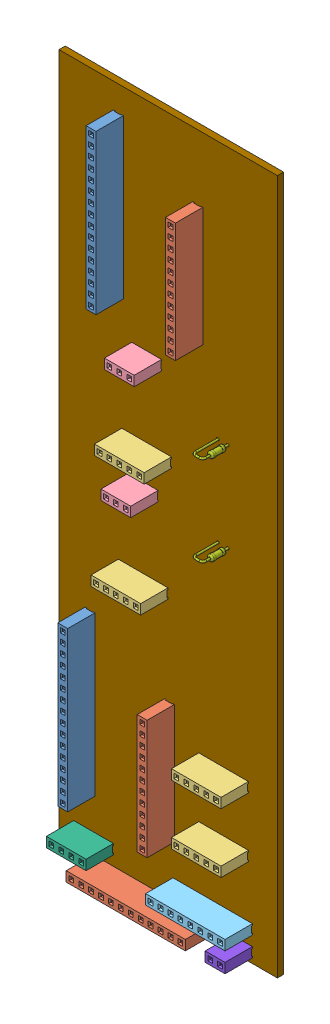
SolidWorks assembly PCB-Step, configuration Default. Lengths in mm.
Overall size (55.88 177.8 10.1).
33 component instances, 9 part files, 0 mates.
Components (placement in the parent):
- PinSocket_1x16_P2.54mm_Vertical.step-1: PinSocket_1x16_P2.54mm_Vertical.step [Default] at (83.82 -25.4 1.65) size (2.54 40.64 10.1)
  - SOLID.step-1: SOLID.step [Default] at origin size (2.54 40.64 10.1)
- PinSocket_1x12_P2.54mm_Vertical.step-1: PinSocket_1x12_P2.54mm_Vertical.step [Default] at (104.14 -35.56 1.65) size (2.54 30.48 10.1)
  - SOLID-0.step-1: SOLID-0.step [Default] at origin size (2.54 30.48 10.1)
- PinSocket_1x05_P2.54mm_Vertical.step-1: PinSocket_1x05_P2.54mm_Vertical.step [Default] at (105.664 -156.972 1.65) x (0 1 0) z (0 0 1) size (2.54 12.7 10.1)
  - SOLID-1.step-1: SOLID-1.step [Default] at origin size (2.54 12.7 10.1)
- PinSocket_1x05_P2.54mm_Vertical.step-2: PinSocket_1x05_P2.54mm_Vertical.step [Default] at (105.664 -172.212 1.65) x (0 1 0) z (0 0 1) size (2.54 12.7 10.1)
  - SOLID-1.step-1: SOLID-1.step [Default] at origin size (2.54 12.7 10.1)
- PinSocket_1x16_P2.54mm_Vertical.step-2: PinSocket_1x16_P2.54mm_Vertical.step [Default] at (76.581 -139.192 1.65) size (2.54 40.64 10.1)
  - SOLID.step-1: SOLID.step [Default] at origin size (2.54 40.64 10.1)
- PinSocket_1x12_P2.54mm_Vertical.step-2: PinSocket_1x12_P2.54mm_Vertical.step [Default] at (96.901 -149.352 1.65) size (2.54 30.48 10.1)
  - SOLID-0.step-1: SOLID-0.step [Default] at origin size (2.54 30.48 10.1)
- PinSocket_1x12_P2.54mm_Vertical.step-3: PinSocket_1x12_P2.54mm_Vertical.step [Default] at (78.74 -193.04 1.65) x (0 1 0) z (0 0 1) size (2.54 30.48 10.1)
  - SOLID-0.step-1: SOLID-0.step [Default] at origin size (2.54 30.48 10.1)
- PinSocket_1x03_P2.54mm_Vertical.step-1: PinSocket_1x03_P2.54mm_Vertical.step [Default] at (88.519 -74.549 1.65) x (0 1 0) z (0 0 1) size (2.54 7.62 10.1)
  - SOLID-2.step-1: SOLID-2.step [Default] at origin size (2.54 7.62 10.1)
- PinSocket_1x05_P2.54mm_Vertical.step-3: PinSocket_1x05_P2.54mm_Vertical.step [Default] at (85.979 -94.869 1.65) x (0 1 0) z (0 0 1) size (2.54 12.7 10.1)
  - SOLID-1.step-1: SOLID-1.step [Default] at origin size (2.54 12.7 10.1)
- PinSocket_1x08_P2.54mm_Vertical.step-1: PinSocket_1x08_P2.54mm_Vertical.step [Default] at (99.06 -187.96 1.65) x (0 1 0) z (0 0 1) size (2.54 20.32 10.1)
  - SOLID-3.step-1: SOLID-3.step [Default] at origin size (2.54 20.32 10.1)
- PinSocket_1x04_P2.54mm_Vertical.step-1: PinSocket_1x04_P2.54mm_Vertical.step [Default] at (73.66 -187.96 1.65) x (0 1 0) z (0 0 1) size (2.54 10.16 10.1)
  - SOLID-4.step-1: SOLID-4.step [Default] at origin size (2.54 10.16 10.1)
- PinSocket_1x03_P2.54mm_Vertical.step-2: PinSocket_1x03_P2.54mm_Vertical.step [Default] at (87.63 -104.013 1.65) x (0 1 0) z (0 0 1) size (2.54 7.62 10.1)
  - SOLID-2.step-1: SOLID-2.step [Default] at origin size (2.54 7.62 10.1)
- PinSocket_1x05_P2.54mm_Vertical.step-4: PinSocket_1x05_P2.54mm_Vertical.step [Default] at (85.09 -124.333 1.65) x (0 1 0) z (0 0 1) size (2.54 12.7 10.1)
  - SOLID-1.step-1: SOLID-1.step [Default] at origin size (2.54 12.7 10.1)
- R_Axial_DIN0204_L3.6mm_D1.6mm_P2.54mm_Vertical.step-1: R_Axial_DIN0204_L3.6mm_D1.6mm_P2.54mm_Vertical.step [Default] at (111.76 -106.68 1.65) x (-1 0 0) z (0 0 1) size (3.59 1.6 9.6)
  - SOLID-5.step-1: SOLID-5.step [Default] at origin size (3.59 1.6 9.6)
- R_Axial_DIN0204_L3.6mm_D1.6mm_P2.54mm_Vertical.step-2: R_Axial_DIN0204_L3.6mm_D1.6mm_P2.54mm_Vertical.step [Default] at (111.76 -83.82 1.65) x (-1 0 0) z (0 0 1) size (3.59 1.6 9.6)
  - SOLID-5.step-1: SOLID-5.step [Default] at origin size (3.59 1.6 9.6)
- PinSocket_1x02_P2.54mm_Vertical.step-1: PinSocket_1x02_P2.54mm_Vertical.step [Default] at (114.3 -193.04 1.65) x (0 1 0) z (0 0 1) size (2.54 5.08 10.1)
  - SOLID-6.step-1: SOLID-6.step [Default] at origin size (2.54 5.08 10.1)
- COMPOUND.step-1: COMPOUND.step [Default] at origin size (55.88 177.8 1.6)
